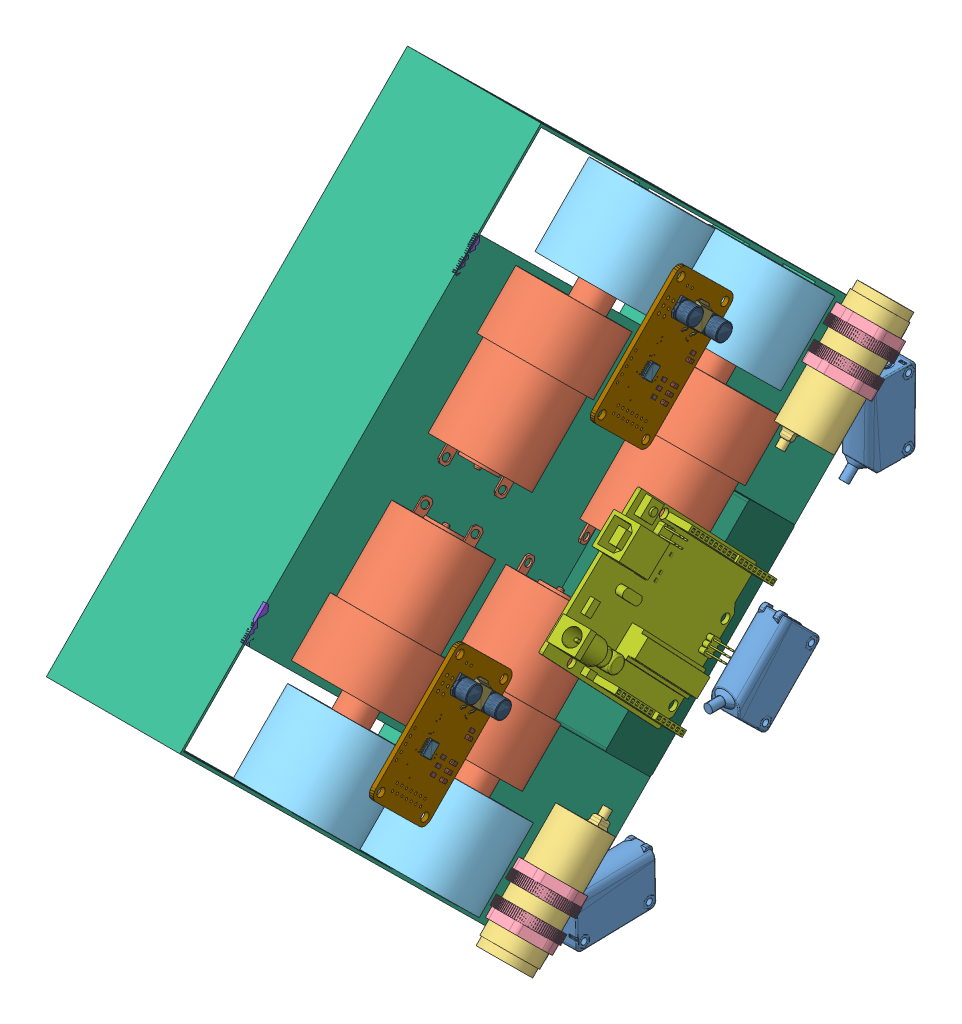
SolidWorks assembly EnsamblajeRobotSumo, configuration Predeterminado. Lengths in mm.
Overall size (131.69 282.84 282.84).
54 component instances, 15 part files, 39 mates.
Components (placement in the parent):
- Pepperl-Fuchs-ML100-8-1000-RT.stp-1: Pepperl-Fuchs-ML100-8-1000-RT.stp [Predeterminado] at (-8.7927 -23.8443 32.6062) x (1 0 0) z (0 -0.025143 0.999684) size (11.02 23.57 34.55)
- Pepperl-Fuchs-ML100-8-1000-RT.stp-2: Pepperl-Fuchs-ML100-8-1000-RT.stp [Predeterminado] at (-8.7927 19.5314 -35.7843) x (1 0 0) z (0 -0.711601 0.702584) size (11.02 23.57 34.55)
- Pepperl-Fuchs-ML100-8-1000-RT.stp-3: Pepperl-Fuchs-ML100-8-1000-RT.stp [Predeterminado] at (-8.7927 86.3709 -86.0307) x (1 0 0) z (0 -0.999944 0.010556) size (11.02 23.57 34.55)
- Titan-37mm-500rpm.stp-1: Titan-37mm-500rpm.stp [Predeterminado] at (-35.3034 88.6826 -32.0272) x (0.060948 0.701278 0.710278) z (0 0.711601 -0.702584) size (37.72 37.72 78.76)
- Titan-37mm-500rpm.stp-2: Titan-37mm-500rpm.stp [Predeterminado] at (-48.9484 133.473 13.338) x (0.310721 -0.667807 -0.676377) z (0 0.711601 -0.702584) size (37.72 37.72 78.76)
- Titan-37mm-500rpm.stp-3: Titan-37mm-500rpm.stp [Predeterminado] at (-48.7615 74.7669 70.5906) x (-0.38284 0.649057 0.657388) z (0 -0.711601 0.702584) size (37.72 37.72 78.76)
- Titan-37mm-500rpm.stp-4: Titan-37mm-500rpm.stp [Predeterminado] at (-49.2797 30.3066 25.5596) x (-0.065964 0.701054 0.710051) z (0 -0.711601 0.702584) size (37.72 37.72 78.76)
- mz80-cad.stp-1: mz80-cad.stp [Predeterminado] at (-7.2927 -19.5107 66.963) x (-1 0 0) z (0 0.711601 -0.702584) size (31.67 31.67 51)
  - MZ80.stp-1: MZ80.stp [Predeterminado] at origin size (19 19 51)
  - MZ80-Kapak.stp-1: MZ80-Kapak.stp [Predeterminado] at (0 0 27.0394) x (-0.689084 -0.724681 0) z (0 0 -1) size (22.4 22.4 7)
  - MZ80-Kapak.stp-2: MZ80-Kapak.stp [Predeterminado] at (0 0 8.0394) x (0.997024 -0.077086 0) z (0 0 1) size (22.4 22.4 7)
- mz80-cad.stp-2: mz80-cad.stp [Predeterminado] at (-7.2927 130.6932 -81.3375) x (0.923728 -0.269124 -0.272578) z (0 -0.711601 0.702584) size (31.67 31.67 51)
  - MZ80.stp-1: MZ80.stp [Predeterminado] at origin size (19 19 51)
  - MZ80-Kapak.stp-1: MZ80-Kapak.stp [Predeterminado] at (0 0 27.0394) x (-0.689084 -0.724681 0) z (0 0 -1) size (22.4 22.4 7)
  - MZ80-Kapak.stp-2: MZ80-Kapak.stp [Predeterminado] at (0 0 8.0394) x (0.997024 -0.077086 0) z (0 0 1) size (22.4 22.4 7)
- js4030-wheel-cad.stp-1: js4030-wheel-cad.stp [Predeterminado] at (-22.0462 75.2548 74.643) x (1 0 0) z (0 -0.711601 0.702584) size (40 40 30.49)
- Part1-1: Part1 [Predeterminado] at (-68.2927 197.0097 -6.2855) x (0 -0.711601 0.702584) z (1 0 0) size (200 200 52)
- js4030-wheel-cad.stp-2: js4030-wheel-cad.stp [Predeterminado] at (-24.1382 143.0895 19.5197) x (0.884077 0.328347 0.332561) z (0 0.711601 -0.702584) size (40 40 30.49)
- js4030-wheel-cad.stp-3: js4030-wheel-cad.stp [Predeterminado] at (-22.1342 92.1406 -32.0831) x (0.992319 0.086914 0.08803) z (0 0.711601 -0.702584) size (40 40 30.49)
- js4030-wheel-cad.stp-4: js4030-wheel-cad.stp [Predeterminado] at (-22.0636 28.1485 26.9321) x (0.997082 -0.053635 -0.054323) z (0 -0.711601 0.702584) size (40 40 30.49)
- uploads_b4_22_56_eb_53_Arduino.ipt.stp-1: uploads_b4_22_56_eb_53_Arduino.ipt.stp [Predeterminado] at (-15.0427 22.4406 0.5554) x (0 -0.725374 -0.688355) z (0 -0.688355 0.725374) size (74.93 14.99 53.34)
- pololu-QTR-1a-1: pololu-QTR-1a [Predeterminado] at (-66.2927 87.2313 -108.6483) x (0 -0.711601 0.702584) z (-1 0 0) size (12.8 7.17 2.73)
- pololu-QTR-1a-2: pololu-QTR-1a [Predeterminado] at (-66.2927 -37.2989 14.3039) x (0 -0.711601 0.702584) z (-1 0 0) size (12.8 7.17 2.73)
- pololu-QTR-1a-3: pololu-QTR-1a [Predeterminado] at (-66.2927 83.6665 95.5456) x (0 -0.711601 0.702584) z (-1 0 0) size (12.8 7.17 2.73)
- pololu-QTR-1a-4: pololu-QTR-1a [Predeterminado] at (-66.2927 166.9239 13.3433) x (0 -0.711601 0.702584) z (-1 0 0) size (12.8 7.17 2.73)
- node-1824x-cad.step-1: node-1824x-cad.step [Predeterminado] at (-13.4427 129.3529 -55.5031) x (0 -0.702583 -0.711602) z (1 0 0) size (30 50 7.5)
  - Board.step-1: Board.step [Predeterminado] at origin size (30 50 1.6)
  - capae-6.6x6.6h5.7.step-1: capae-6.6x6.6h5.7.step [Predeterminado] at (-55.5301 -11.5859 0) x (0 -1 0) z (0 0 1) size (6.64 6.64 5.89)
  - capae-6.6x6.6h5.7.step-2: capae-6.6x6.6h5.7.step [Predeterminado] at (-39.9374 -11.3677 0) x (0 -1 0) z (0 0 1) size (6.64 6.64 5.89)
  - dio_0805.step-1: dio_0805.step [Predeterminado] at (-40.8591 -36.3956 0) x (-1 0 0) z (0 0 1) size (2.04 1.28 1.28)
  - dio_0805.step-2: dio_0805.step [Predeterminado] at (-40.8591 -33.6079 0) x (-1 0 0) z (0 0 1) size (2.04 1.28 1.28)
  - dio_0805.step-3: dio_0805.step [Predeterminado] at (-40.8591 -30.8201 0) x (-1 0 0) z (0 0 1) size (2.04 1.28 1.28)
  - dio_0805.step-4: dio_0805.step [Predeterminado] at (-40.3443 -22.7571 0) x (-1 0 0) z (0 0 1) size (2.04 1.28 1.28)
  - to252-3_9.6x6.6x2.28.step-1: to252-3_9.6x6.6x2.28.step [Predeterminado] at (-47.7789 -14.8338 0) x (-1 0 0) z (0 0 1) size (7.65 12.33 2.63)
  - res_0805.step-1: res_0805.step [Predeterminado] at (-45.9391 -36.3956 0) x (-1 0 0) z (0 0 1) size (2.04 1.28 0.32)
  - res_0805.step-2: res_0805.step [Predeterminado] at (-45.9391 -33.6079 0) x (-1 0 0) z (0 0 1) size (2.04 1.28 0.32)
  - res_0805.step-3: res_0805.step [Predeterminado] at (-45.9391 -30.8201 0) x (-1 0 0) z (0 0 1) size (2.04 1.28 0.32)
  - res_0805.step-4: res_0805.step [Predeterminado] at (-40.2785 -20.5814 0) x (-1 0 0) z (0 0 1) size (2.04 1.28 0.32)
  - tssop-14.step-1: tssop-14.step [Predeterminado] at (-54.0357 -30.6644 0) x (0 1 0) z (0 0 1) size (5.29 6.86 1.33)
- node-1824x-cad.step-2: node-1824x-cad.step [Predeterminado] at (-13.4427 45.0953 30.4989) x (0 -0.702584 -0.711601) z (1 0 0) size (30 50 7.5)
  - Board.step-1: Board.step [Predeterminado] at origin size (30 50 1.6)
  - capae-6.6x6.6h5.7.step-1: capae-6.6x6.6h5.7.step [Predeterminado] at (-55.5301 -11.5859 0) x (0 -1 0) z (0 0 1) size (6.64 6.64 5.89)
  - capae-6.6x6.6h5.7.step-2: capae-6.6x6.6h5.7.step [Predeterminado] at (-39.9374 -11.3677 0) x (0 -1 0) z (0 0 1) size (6.64 6.64 5.89)
  - dio_0805.step-1: dio_0805.step [Predeterminado] at (-40.8591 -36.3956 0) x (-1 0 0) z (0 0 1) size (2.04 1.28 1.28)
  - dio_0805.step-2: dio_0805.step [Predeterminado] at (-40.8591 -33.6079 0) x (-1 0 0) z (0 0 1) size (2.04 1.28 1.28)
  - dio_0805.step-3: dio_0805.step [Predeterminado] at (-40.8591 -30.8201 0) x (-1 0 0) z (0 0 1) size (2.04 1.28 1.28)
  - dio_0805.step-4: dio_0805.step [Predeterminado] at (-40.3443 -22.7571 0) x (-1 0 0) z (0 0 1) size (2.04 1.28 1.28)
  - to252-3_9.6x6.6x2.28.step-1: to252-3_9.6x6.6x2.28.step [Predeterminado] at (-47.7789 -14.8338 0) x (-1 0 0) z (0 0 1) size (7.65 12.33 2.63)
  - res_0805.step-1: res_0805.step [Predeterminado] at (-45.9391 -36.3956 0) x (-1 0 0) z (0 0 1) size (2.04 1.28 0.32)
  - res_0805.step-2: res_0805.step [Predeterminado] at (-45.9391 -33.6079 0) x (-1 0 0) z (0 0 1) size (2.04 1.28 0.32)
  - res_0805.step-3: res_0805.step [Predeterminado] at (-45.9391 -30.8201 0) x (-1 0 0) z (0 0 1) size (2.04 1.28 0.32)
  - res_0805.step-4: res_0805.step [Predeterminado] at (-40.2785 -20.5814 0) x (-1 0 0) z (0 0 1) size (2.04 1.28 0.32)
  - tssop-14.step-1: tssop-14.step [Predeterminado] at (-54.0357 -30.6644 0) x (0 1 0) z (0 0 1) size (5.29 6.86 1.33)
- Bateria-1: Bateria [Predeterminado] at (-25.7927 -4.2799 -8.5018) x (0 0.711601 -0.702584) z (0 0.702584 0.711601) size (80 40 25)
Mates (geometry in assembly coordinates):
- Concentric2: concentric: cylinder of assembly; cylinder of assembly; cylinder of Titan-37mm-500rpm.stp-2 through (-42.2927 150.3011 -0.2192) axis (0 0.711601 -0.702584) radius 6; cylinder of Part1-1 through (-42.2927 164.5331 -14.2709) axis (0 -0.711601 0.702584) radius 6
- Concentric3: concentric: cylinder of assembly; cylinder of assembly; cylinder of Titan-37mm-500rpm.stp-1 through (-42.2927 104.2818 -46.8291) axis (0 0.711601 -0.702584) radius 6; cylinder of Part1-1 through (-42.2927 114.9558 -57.3679) axis (0 -0.711601 0.702584) radius 6
- Concentric5: concentric: cylinder of assembly; cylinder of assembly; cylinder of Titan-37mm-500rpm.stp-3 through (-42.2927 61.3509 87.6037) axis (0 -0.711601 0.702584) radius 6; cylinder of Part1-1 through (-42.2927 164.5331 -14.2709) axis (0 -0.711601 0.702584) radius 6
- Concentric6: concentric: cylinder of assembly; cylinder of assembly; cylinder of Titan-37mm-500rpm.stp-4 through (-42.2927 15.3317 40.9939) axis (0 -0.711601 0.702584) radius 6; cylinder of Part1-1 through (-42.2927 114.9558 -57.3679) axis (0 -0.711601 0.702584) radius 6
- Coincident3: coincident: plane of assembly; plane of assembly; plane of Titan-37mm-500rpm.stp-4 through (-49.2797 15.0072 40.6652) normal (0 -0.711601 0.702584); plane of Part1-1 through (-16.2927 -19.0949 6.1254) normal (0 0.711601 -0.702584)
- Coincident4: coincident: plane of assembly; plane of assembly; plane of Titan-37mm-500rpm.stp-3 through (-48.7615 59.4675 85.6961) normal (0 -0.711601 0.702584); plane of Part1-1 through (-16.2927 40.976 66.9673) normal (0 0.711601 -0.702584)
- Coincident5: coincident: plane of assembly; plane of assembly; plane of Titan-37mm-500rpm.stp-2 through (-48.9484 148.7724 -1.7675) normal (0 0.711601 -0.702584); plane of Part1-1 through (-16.2927 166.8118 16.5034) normal (0 -0.711601 0.702584)
- Coincident6: coincident: plane of assembly; plane of assembly; plane of Titan-37mm-500rpm.stp-1 through (-35.3034 103.982 -47.1328) normal (0 0.711601 -0.702584); plane of Part1-1 through (-16.2927 124.6568 -26.1927) normal (0 -0.711601 0.702584)
- Concentric8: concentric: cylinder of assembly; cylinder of assembly; cylinder of mz80-cad.stp-1/MZ80.stp-1 through (-7.2927 -17.3758 64.8553) axis (0 0.711601 -0.702584) radius 9.5; cylinder of Part1-1 through (-7.2927 126.7514 -77.4456) axis (0 -0.711601 0.702584) radius 10
- Coincident9: coincident: plane of assembly; plane of assembly; plane of mz80-cad.stp-1/MZ80-Kapak.stp-2 through (-7.2927 -13.7898 61.3147) normal (0 -0.711601 0.702584); plane of Part1-1 through (-16.2927 9.0441 84.4417) normal (0 0.711601 -0.702584)
- Concentric9: concentric: cylinder of assembly; cylinder of assembly; cylinder of mz80-cad.stp-2/MZ80.stp-1 through (-7.2927 128.5584 -79.2297) axis (0 -0.711601 0.702584) radius 9.5; cylinder of Part1-1 through (-7.2927 126.7514 -77.4456) axis (0 -0.711601 0.702584) radius 10
- Coincident10: coincident: plane of assembly; plane of assembly; plane of mz80-cad.stp-2/MZ80-Kapak.stp-2 through (-7.2927 124.9724 -75.6891) normal (0 0.711601 -0.702584); plane of Part1-1 through (-16.2927 149.5628 -50.7831) normal (0 -0.711601 0.702584)
- Coincident11: coincident: plane of assembly; plane of assembly; plane of Pepperl-Fuchs-ML100-8-1000-RT.stp-2 through (-8.7927 24.2418 -44.8196) normal (0 -0.702584 -0.711601); plane of Part1-1 through (-16.2927 68.9559 -88.9671) normal (0 0.702584 0.711601)
- Coincident14: coincident: plane of assembly; plane of assembly; plane of Pepperl-Fuchs-ML100-8-1000-RT.stp-2 through (-14.2927 32.1406 -52.6182) normal (-1 0 0); plane of Part1-1 through (-14.2927 38.1618 -46.1899) normal (1 0 0)
- Coincident17: coincident: plane of assembly; plane of assembly; plane of Pepperl-Fuchs-ML100-8-1000-RT.stp-1 through (-8.7927 -26.7194 22.8309) normal (0 -0.999684 -0.025143); plane of Part1-1 through (-16.2927 -26.2723 5.0545) normal (0 0.999684 0.025143)
- Coincident18: coincident: plane of assembly; plane of assembly; plane of Pepperl-Fuchs-ML100-8-1000-RT.stp-1 through (-14.2927 -26.4403 11.7344) normal (-1 0 0); plane of Part1-1 through (-14.2927 -5.0432 20.3574) normal (1 0 0)
- Coincident19: coincident: plane of assembly; plane of assembly; plane of Pepperl-Fuchs-ML100-8-1000-RT.stp-3 through (-8.7927 96.0374 -89.253) normal (0 -0.010556 -0.999944); plane of Part1-1 through (-16.2927 111.4201 -89.4154) normal (0 0.010556 0.999944)
- Coincident20: coincident: plane of assembly; plane of assembly; plane of Pepperl-Fuchs-ML100-8-1000-RT.stp-3 through (-14.2927 107.1368 -89.3701) normal (-1 0 0); plane of Part1-1 through (-14.2927 24.4412 -8.7534) normal (1 0 0)
- Concentric10: concentric: cylinder of assembly; cylinder of assembly; cylinder of Titan-37mm-500rpm.stp-1 through (-42.2927 108.5514 -51.0446) axis (0 0.711601 -0.702584) radius 3; cylinder of js4030-wheel-cad.stp-3 through (-42.2927 129.8995 -72.1221) axis (0 -0.711601 0.702584) radius 3
- Coincident21: coincident: plane of assembly; plane of assembly; plane of Titan-37mm-500rpm.stp-1 through (-42.2927 108.5514 -51.0446) normal (0 0.711601 -0.702584); plane of js4030-wheel-cad.stp-3 through (-42.2927 108.5514 -51.0446) normal (0 -0.711601 0.702584)
- Concentric11: concentric: cylinder of assembly; cylinder of assembly; cylinder of Titan-37mm-500rpm.stp-3 through (-42.2927 57.0813 91.8192) axis (0 -0.711601 0.702584) radius 3; cylinder of js4030-wheel-cad.stp-1 through (-42.2927 35.7333 112.8968) axis (0 0.711601 -0.702584) radius 3
- Coincident22: coincident: plane of assembly; plane of assembly; plane of Titan-37mm-500rpm.stp-3 through (-42.2927 57.0813 91.8192) normal (0 -0.711601 0.702584); plane of js4030-wheel-cad.stp-1 through (-42.2927 57.0813 91.8192) normal (0 0.711601 -0.702584)
- Concentric12: concentric: cylinder of assembly; cylinder of assembly; cylinder of Titan-37mm-500rpm.stp-4 through (-42.2927 11.0621 45.2094) axis (0 -0.711601 0.702584) radius 3; cylinder of js4030-wheel-cad.stp-4 through (-42.2927 -10.2859 66.2869) axis (0 0.711601 -0.702584) radius 3
- Coincident23: coincident: plane of assembly; plane of assembly; plane of Titan-37mm-500rpm.stp-4 through (-42.2927 11.0621 45.2094) normal (0 -0.711601 0.702584); plane of js4030-wheel-cad.stp-4 through (-42.2927 11.0621 45.2094) normal (0 0.711601 -0.702584)
- Concentric13: concentric: cylinder of assembly; cylinder of assembly; cylinder of Titan-37mm-500rpm.stp-2 through (-42.2927 154.5707 -4.4347) axis (0 0.711601 -0.702584) radius 3; cylinder of js4030-wheel-cad.stp-2 through (-42.2927 175.9187 -25.5123) axis (0 -0.711601 0.702584) radius 3
- Coincident24: coincident: plane of assembly; plane of assembly; plane of Titan-37mm-500rpm.stp-2 through (-42.2927 154.5707 -4.4347) normal (0 0.711601 -0.702584); plane of js4030-wheel-cad.stp-2 through (-42.2927 154.5707 -4.4347) normal (0 -0.711601 0.702584)
- Coincident25: coincident: plane of assembly; plane of assembly; plane of Part1-1 through (-15.0427 334.7189 133.1911) normal (1 0 0); plane of uploads_b4_22_56_eb_53_Arduino.ipt.stp-1 through (-15.0427 64.2468 3.638) normal (-1 0 0)
- Coincident29: coincident: line of assembly; line of assembly; line of Part1-1 through (-66.2927 83.1604 -94.553) axis (0 0.711601 -0.702584); line of pololu-QTR-1a-1 through (-66.2927 83.1604 -94.553) axis (0 0.711601 -0.702584)
- Coincident30: coincident: line of assembly; line of assembly; line of Part1-1 through (-66.2927 78.1017 -99.6766) axis (0 0.702584 0.711601); line of pololu-QTR-1a-1 through (-66.2927 78.1228 -99.6552) axis (0 0.702584 0.711601)
- Coincident31: coincident: line of assembly; line of assembly; line of Part1-1 through (-66.2927 -41.3698 28.3991) axis (0 0.711601 -0.702584); line of pololu-QTR-1a-2 through (-66.2927 -41.3698 28.3991) axis (0 0.711601 -0.702584)
- Coincident32: coincident: line of assembly; line of assembly; line of Part1-1 through (-66.2927 -46.4284 23.2756) axis (0 0.702584 0.711601); line of pololu-QTR-1a-2 through (-66.2927 -46.4073 23.297) axis (0 0.702584 0.711601)
- Coincident33: coincident: line of assembly; line of assembly; line of Part1-1 through (-66.2927 162.8529 27.4385) axis (0 0.711601 -0.702584); line of pololu-QTR-1a-4 through (-66.2927 162.8529 27.4385) axis (0 0.711601 -0.702584)
- Coincident34: coincident: line of assembly; line of assembly; line of Part1-1 through (-66.2927 157.7943 22.315) axis (0 0.702584 0.711601); line of pololu-QTR-1a-4 through (-66.2927 157.8154 22.3363) axis (0 0.702584 0.711601)
- Coincident35: coincident: line of assembly; line of assembly; line of Part1-1 through (-66.2927 79.5956 109.6408) axis (0 0.711601 -0.702584); line of pololu-QTR-1a-3 through (-66.2927 79.5956 109.6408) axis (0 0.711601 -0.702584)
- Coincident36: coincident: line of assembly; line of assembly; line of Part1-1 through (-66.2927 74.537 104.5173) axis (0 0.702584 0.711601); line of pololu-QTR-1a-3 through (-66.2927 74.5581 104.5386) axis (0 0.702584 0.711601)
- Coincident37: coincident: plane of assembly; plane of assembly; plane of Part1-1 through (-15.0427 334.7189 133.1911) normal (1 0 0); plane of node-1824x-cad.step-2/Board.step-1 through (-15.0427 53.3065 110.927) normal (-1 0 0)
- Coincident44: coincident: plane of assembly; plane of assembly; plane of Part1-1 through (-15.0427 334.7189 133.1911) normal (1 0 0); plane of node-1824x-cad.step-1/Board.step-1 through (-15.0427 137.564 24.9251) normal (-1 0 0)
- Coincident45: coincident: plane of assembly; plane of assembly; plane of Part1-1 through (-65.7927 197.0097 -6.2855) normal (1 0 0); plane of Bateria-1 through (-65.7927 13.2847 9.2882) normal (-1 0 0)
- Coincident46: coincident: plane of assembly; plane of assembly; plane of Part1-1 through (-16.2927 69.8552 -81.6976) normal (0 0.702584 0.711601); plane of Bateria-1 through (-25.7927 -4.2799 -8.5018) normal (0 -0.702584 -0.711601)
